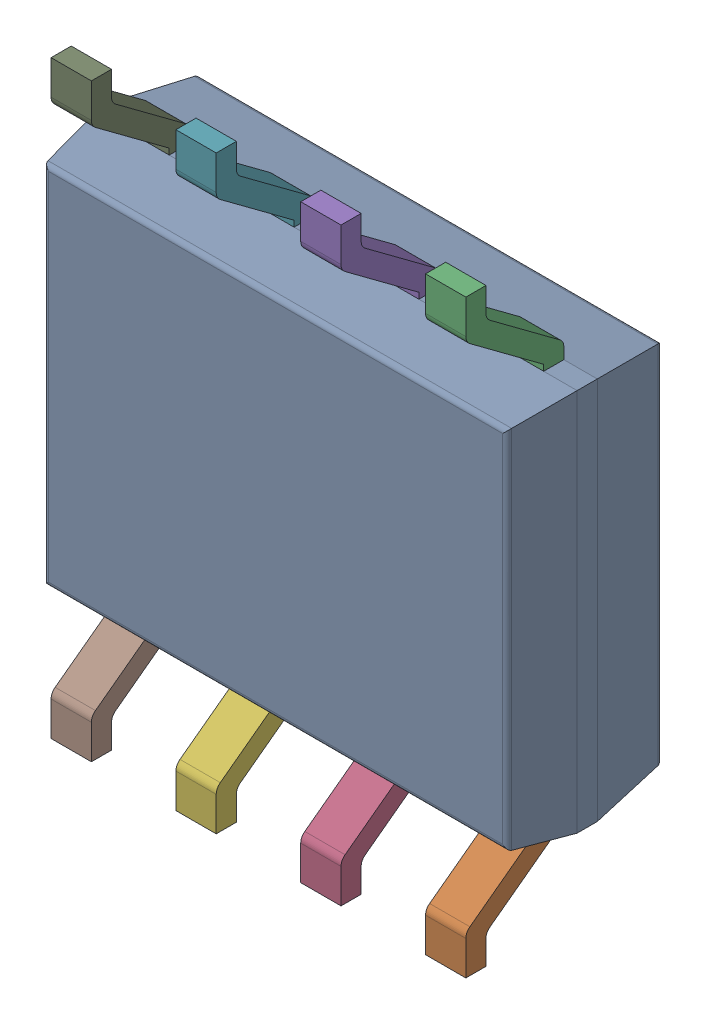
SolidWorks assembly IC3, configuration Default. Lengths in mm.
Overall size (4.9 6 1.75).
3 component instances, 2 part files, 0 mates.
Components (placement in the parent):
- 10172115792-1: 10172115792 [Default] at (116.332 112.522 -1.0914) x (0 1 0) z (0 0 -1) size (6 4.9 1.75)
  - Body-0-1: Body-0 [Default] at origin size (3.9 4.9 1.57)
  - PinsArrayLR-1-1: PinsArrayLR-1 [Default] at origin size (6 4.22 1)
